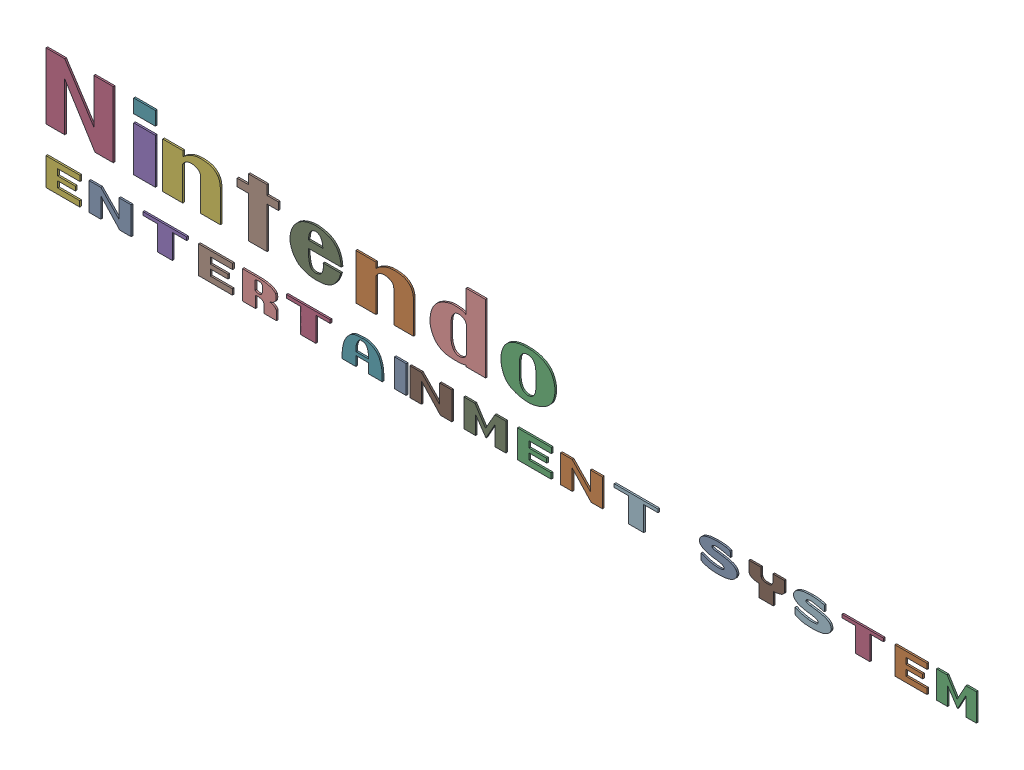
SolidWorks assembly Nintendo Text, configuration Default. Lengths in mm.
Overall size (72.21 9.55 0.13).
3 component instances, 3 part files, 0 mates.
Components (placement in the parent):
- Text3D - ENTERTAINMENT-1: Text3D - ENTERTAINMENT [Default] at (-177.0237 42.8806 189.646) x (-1 0 0) z (0 0 1) size (47.5 2.19 0.13)
- Text3D - Nintendo-1: Text3D - Nintendo [Default] at (-177.0237 47.1471 200) x (-1 0 0) z (0 0 1) size (39.5 5.28 0.13)
- Text3D - SYSTEM-1: Text3D - SYSTEM [Default] at (-126.3184 42.989 188.4705) x (-1 0 0) z (0 0 1) size (21.5 2.18 0.13)
